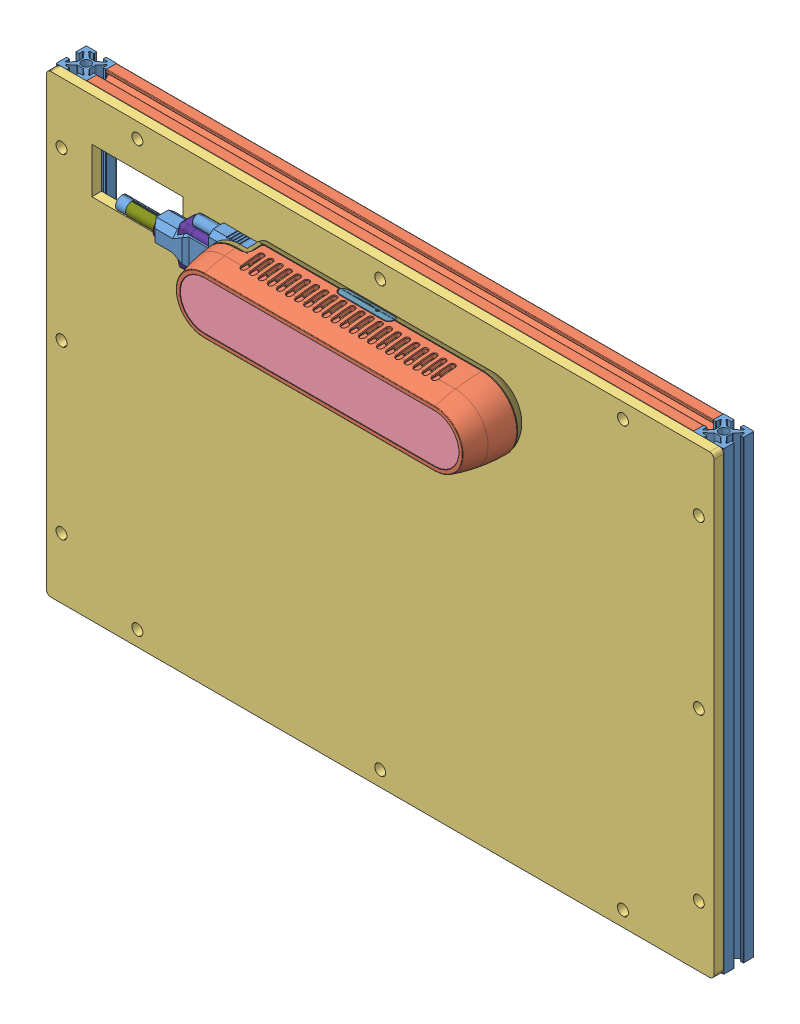
SolidWorks assembly Front Panel, configuration Default. Lengths in mm.
Overall size (220 150 33.22).
43 component instances, 26 part files, 17 mates.
Components (placement in the parent):
- Makerbeam_150mm.stp-1: Makerbeam_150mm.stp [Default] at (105 -75 -5) x (-1 0 0) z (0 1 0) size (10 10 150)
- Makerbeam_200mm.stp-1: Makerbeam_200mm.stp [Default] at (-100 -70 -5) x (0 0 -1) z (1 0 0) size (10 10 200)
- Acrylic Side Panel FRONT-1: Acrylic Side Panel FRONT [Default] at origin size (220 150 3.17)
- Makerbeam_150mm.stp-2: Makerbeam_150mm.stp [Default] at (-105 -75 -5) x (-1 0 0) z (0 1 0) size (10 10 150)
- Makerbeam_200mm.stp-2: Makerbeam_200mm.stp [Default] at (-100 70 -5) x (0 0 -1) z (1 0 0) size (10 10 200)
- Intel_RealSense_D415.stp-1: Intel_RealSense_D415.stp [Default] at (0 53.5 23.225) size (130.85 23.53 20.08)
  - LENS_COVER_SUBASSY_ASRC_ASM.stp-1: LENS_COVER_SUBASSY_ASRC_ASM.stp [Default] at origin size (91.8 15.8 0.7)
    - LENS_COVER_ASRC.stp-1: LENS_COVER_ASRC.stp [Default] at origin size (91.8 15.8 0.55)
    - MASK_LENS_COVER_ASRC.stp-1: MASK_LENS_COVER_ASRC.stp [Default] at origin size (91.8 15.8 0.03)
    - ADHESIVE_LENS_COVER_ASRC.stp-1: ADHESIVE_LENS_COVER_ASRC.stp [Default] at origin size (91.2 15.2 0.13)
  - FOAM_ISOLATION_W_CARRIER_ASRC_ASM.stp-1: FOAM_ISOLATION_W_CARRIER_ASRC_ASM.stp [Default] at origin size (85.1 11.4 0.58)
    - DS5_0390_FOAM_FRONT.stp-1: DS5_0390_FOAM_FRONT.stp [Default] at origin size (85.1 11.4 0.53)
    - DS5_0390_ADHESIVE.stp-1: DS5_0390_ADHESIVE.stp [Default] at (0 0 -0.2) size (85.1 11.4 0.05)
  - CAMERA_MOD_DS5_ASRC_ASM.stp-1: CAMERA_MOD_DS5_ASRC_ASM.stp [Default] at (13.5 0 -6.04) x (1 0 0) z (0 -1 0) size (83.7 4.7 10)
    - IDC-DS-0601_ASRC_SW0001_1_ASM.stp-1: IDC-DS-0601_ASRC_SW0001_1_ASM.stp [Default] at origin size (83.7 4.7 10)
      - IDC-DS-0601_ASRC_SW0001_1_1.stp-1: IDC-DS-0601_ASRC_SW0001_1_1.stp [Default] at origin size (83.7 4.7 10)
  - LABEL_ASRC_CAMERA_MODULE_ASM.stp-1: LABEL_ASRC_CAMERA_MODULE_ASM.stp [Default] at origin size (82.7 9 0.55)
    - DS5_0390_LABEL_FRONT_MODULE.stp-1: DS5_0390_LABEL_FRONT_MODULE.stp [Default] at origin size (82.7 9 0.55)
    - DS5_0390_LABEL_FRONT_ADHESIVE.stp-1: DS5_0390_LABEL_FRONT_ADHESIVE.stp [Default] at origin size (82.7 9 0.03)
  - REAR_COVER_SUBASSY_ASRC_ASM.stp-1: REAR_COVER_SUBASSY_ASRC_ASM.stp [Default] at origin size (99.28 23.01 10.39)
    - REAR_COVER_ALUMINUM_ASRC.stp-1: REAR_COVER_ALUMINUM_ASRC.stp [Default] at origin size (99.28 23.01 10.39)
    - MAGNET.stp-1: MAGNET.stp [Default] at (-7.25 8.4 -15.54) x (-1 0 0) z (0 1 0) size (1.6 1.6 1.6)
    - MAGNET.stp-2: MAGNET.stp [Default] at (7.25 8.4 -15.54) x (-1 0 0) z (0 1 0) size (1.6 1.6 1.6)
  - AUX_COVER_SUBASSY_ASRC_ASM.stp-1: AUX_COVER_SUBASSY_ASRC_ASM.stp [Default] at origin size (17.9 3.6 3.42)
    - AUX_COVER_ALUMINUM_ASRC.stp-1: AUX_COVER_ALUMINUM_ASRC.stp [Default] at origin size (17.9 3.6 3.42)
    - PIN_STEEL_ZINC_PLATED.stp-1: PIN_STEEL_ZINC_PLATED.stp [Default] at (-7.25 10 -15.54) x (1 0 0) z (0 -1 0) size (1.6 1.6 1.6)
    - PIN_STEEL_ZINC_PLATED.stp-2: PIN_STEEL_ZINC_PLATED.stp [Default] at (7.25 10 -15.54) x (1 0 0) z (0 -1 0) size (1.6 1.6 1.6)
  - USB_TYPE-C_PLUG_-1_ASM.stp-1: USB_TYPE-C_PLUG_-1_ASM.stp [Default] at (-36.1 0 -15.875) x (0 -1 0) z (1 0 0) size (13.06 6.7 48.1)
    - USB_TYPE-C_PLUG_-1_1_ASM.stp-1: USB_TYPE-C_PLUG_-1_1_ASM.stp [Default] at origin size (13.06 6.7 48.1)
      - BOSS-EXTRUDE3.stp-1: BOSS-EXTRUDE3.stp [Default] at origin size (4.2 4.2 10)
      - FILLET11.stp-1: FILLET11.stp [Default] at origin size (13.06 6.7 31.5)
      - BOSS-EXTRUDE4.stp-1: BOSS-EXTRUDE4.stp [Default] at origin size (8.3 2.45 6.6)
  - LOCKING_CTYPE_USB_ASM.stp-1: LOCKING_CTYPE_USB_ASM.stp [Default] at (-36.15 0 -15.92) size (51.45 18.5 8)
    - LOCKING_C_TYPE_USB.stp-1: LOCKING_C_TYPE_USB.stp [Default] at origin size (48.3 18.5 8)
    - BOSS-EXTRUDE4.stp-1: BOSS-EXTRUDE4.stp [Default] at (6.65 -0.005 -0.005) x (0 -1 0) z (-1 0 0) size (8.3 2.45 6.6)
  - FRONT_COVER_ALUMINUM_ASRC.stp-1: FRONT_COVER_ALUMINUM_ASRC.stp [Default] at origin size (98.75 23.53 15.66)
  - HEATSINK_ASRC.stp-1: HEATSINK_ASRC.stp [Default] at origin size (94.31 20.8 12.15)
  - BRACKET_CAMERA_MODULE_ASRC.stp-1: BRACKET_CAMERA_MODULE_ASRC.stp [Default] at (5.175 0.35 -6.01) x (-1 0 0) z (0 1 0) size (21 5.77 15.8)
  - BRACKET_B2B_CONN_SUPPORT_ASRC.stp-1: BRACKET_B2B_CONN_SUPPORT_ASRC.stp [Default] at (5.2 -5.1 -0.87) size (14.5 6.47 1.64)
  - SCREW_TORX_M1-6_X_4L.stp-1: SCREW_TORX_M1-6_X_4L.stp [Default] at (-0.375 6.95 -7.86) size (3.2 3.2 5.3)
  - SCREW_TORX_M1-6_X_4L.stp-2: SCREW_TORX_M1-6_X_4L.stp [Default] at (10.725 6.95 -7.86) size (3.2 3.2 5.3)
  - SCREW_TORX_M2_X_5L.stp-1: SCREW_TORX_M2_X_5L.stp [Default] at (-39.8 0 -12.04) x (-1 0 0) z (0 0 -1) size (4 4 5)
  - BARCODE.stp-1: BARCODE.stp [Default] at (0 -9.728 -1.7983) x (-1 0 0) z (0 -0.968461 0.249165) size (70 5.5 0.09)
Mates (geometry in assembly coordinates):
- Coincident1: coordinate: point of Acrylic Side Panel FRONT-1
- Coincident2: coincident anti-aligned: plane of Acrylic Side Panel FRONT-1 through (0 0 0) normal (0 0 -1); plane of Makerbeam_200mm.stp-1 through (-100 -74.8 0) normal (0 0 1)
- Coincident4: coincident aligned: plane of Makerbeam_200mm.stp-1 through (-100 -75 -3.3) normal (0 -1 0); plane of Acrylic Side Panel FRONT-1 through (0 -75 3.175) normal (0 -1 0)
- Coincident5: coincident aligned: plane of Makerbeam_150mm.stp-1 through (105 -75 -5) normal (0 -1 0); plane of Acrylic Side Panel FRONT-1 through (0 -75 3.175) normal (0 -1 0)
- Coincident6: coincident anti-aligned: plane of Makerbeam_150mm.stp-1 through (109.8 -75 0) normal (0 0 1); plane of Acrylic Side Panel FRONT-1 through (0 0 0) normal (0 0 -1)
- Coincident7: coincident aligned: plane of Makerbeam_150mm.stp-1 through (105 75 -5) normal (0 1 0); plane of Acrylic Side Panel FRONT-1 through (0 75 3.175) normal (0 1 0)
- Coincident8: coincident aligned: plane of Makerbeam_150mm.stp-1 through (110 -75 -9.8) normal (1 0 0); plane of Acrylic Side Panel FRONT-1 through (110 0 3.175) normal (1 0 0)
- Coincident9: coincident anti-aligned: plane of Makerbeam_150mm.stp-1 through (100 -75 -6.7) normal (-1 0 0); plane of Makerbeam_200mm.stp-1 through (100 -70 -5) normal (1 0 0)
- Coincident10: coincident aligned: plane of Acrylic Side Panel FRONT-1 through (0 -75 3.175) normal (0 -1 0); plane of Makerbeam_150mm.stp-2 through (-105 -75 -5) normal (0 -1 0)
- Coincident11: coincident anti-aligned: plane of Acrylic Side Panel FRONT-1 through (0 0 0) normal (0 0 -1); plane of Makerbeam_150mm.stp-2 through (-106.7 -75 0) normal (0 0 1)
- Coincident12: coincident anti-aligned: plane of Makerbeam_200mm.stp-1 through (-100 -70 -5) normal (-1 0 0); plane of Makerbeam_150mm.stp-2 through (-100 -75 -9.8) normal (1 0 0)
- Coincident13: coincident anti-aligned: plane of Acrylic Side Panel FRONT-1 through (0 0 0) normal (0 0 -1); plane of Makerbeam_200mm.stp-2 through (-100 71.7 0) normal (0 0 1)
- Coincident14: coincident anti-aligned: plane of Makerbeam_150mm.stp-1 through (100 -75 -0.2) normal (-1 0 0); plane of Makerbeam_200mm.stp-2 through (100 70 -5) normal (1 0 0)
- Coincident15: coincident aligned: plane of Makerbeam_150mm.stp-1 through (105 75 -5) normal (0 1 0); plane of Makerbeam_200mm.stp-2 through (-100 75 -0.2) normal (0 1 0)
- Concentric1: concentric aligned: cylinder of Acrylic Side Panel FRONT-1 through (22.5 53.5 3.175) axis (0 0 1) radius 1.8; cylinder of Intel_RealSense_D415.stp-1/REAR_COVER_SUBASSY_ASRC_ASM.stp-1/REAR_COVER_ALUMINUM_ASRC.stp-1 through (22.5 53.5 3.175) axis (0 0 1) radius 1.25
- Concentric2: concentric aligned: cylinder of Acrylic Side Panel FRONT-1 through (-22.5 53.5 3.175) axis (0 0 1) radius 1.8; cylinder of Intel_RealSense_D415.stp-1/REAR_COVER_SUBASSY_ASRC_ASM.stp-1/REAR_COVER_ALUMINUM_ASRC.stp-1 through (-22.5 53.5 3.175) axis (0 0 1) radius 1.25
- Coincident16: coincident anti-aligned: plane of Acrylic Side Panel FRONT-1 through (0 0 3.175) normal (0 0 1); plane of Intel_RealSense_D415.stp-1/REAR_COVER_SUBASSY_ASRC_ASM.stp-1/REAR_COVER_ALUMINUM_ASRC.stp-1 through (0 53.5 3.175) normal (0 0 -1)
